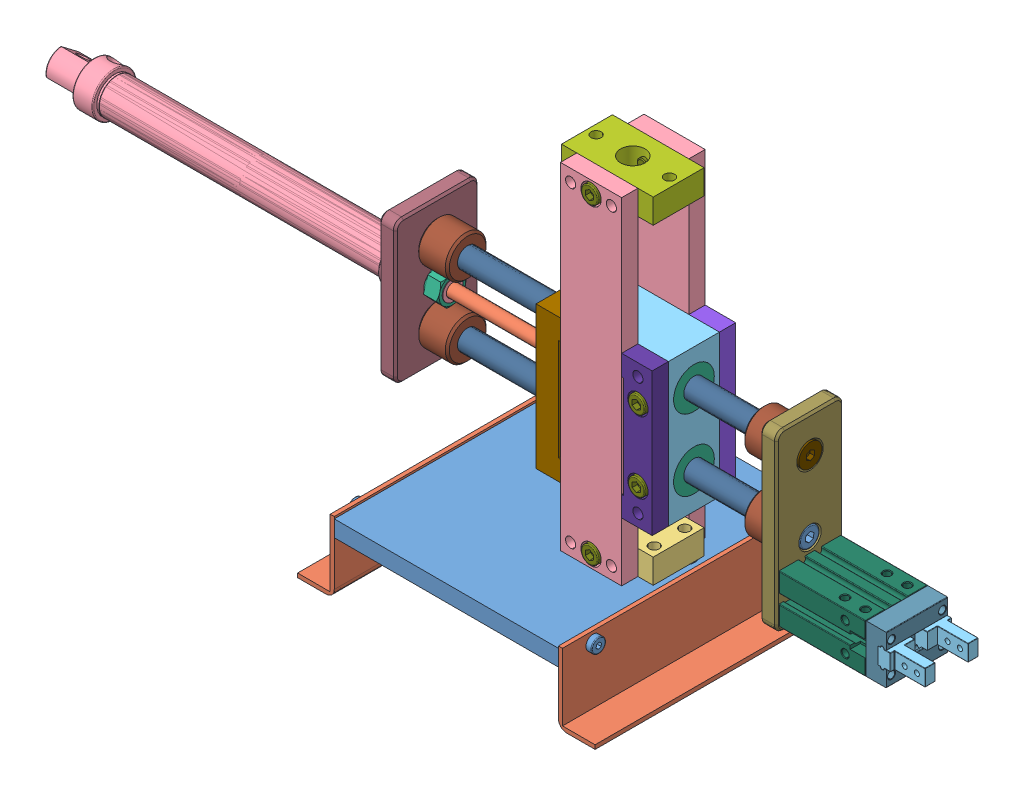
SolidWorks assembly S4, configuration Default. Lengths in mm.
Overall size (436.7 199 125).
52 component instances, 24 part files, 126 mates.
Components (placement in the parent):
- tam de lon-1: tam de lon [Default] at (42.5889 56.6685 101.1963) size (110 8 125)
- khoi do-1: khoi do [Default] at (98.4472 49.4552 163.6963) x (0 0 -1) z (-1 0 0) size (125 35 18)
- khoi do-2: khoi do [Default] at (-13.2695 49.4552 38.6963) x (0 0 1) z (1 0 0) size (125 35 18)
- mieng dem duoi-1: mieng dem duoi [Default] at (71.5889 64.6685 101.1963) size (45 12 25)
- thanh dan huong lon x2-1: thanh dan huong lon x2 [Default] at (71.5889 147.1685 113.6963) x (1 0 0) z (0 -1 0) size (30 8 165)
- thanh dan huong lon x2-2: thanh dan huong lon x2 [Default] at (71.5889 147.1685 88.6963) x (1 0 0) z (0 1 0) size (30 8 165)
- con truot s4 -1: con truot s4  [Default] at (79.0889 93.5395 101.1963) x (-1 0 0) z (0 0 -1) size (45 70 25)
- bac lot-1: bac lot [Default] at (101.5889 111.0395 101.1963) x (0 1 0) z (0 0 1) size (20 12 20)
- bac lot-2: bac lot [Default] at (101.5889 146.0395 101.1963) x (0 1 0) z (0 0 1) size (20 12 20)
- bac lot-3: bac lot [Default] at (56.5889 146.0395 101.1963) x (0 0.381849 -0.924225) z (0 -0.924225 -0.381849) size (20 12 20)
- bac lot-4: bac lot [Default] at (56.5889 111.0395 101.1963) x (0 0.381849 -0.924225) z (0 -0.924225 -0.381849) size (20 12 20)
- mieng dem tren-1: mieng dem tren [Default] at (71.5889 217.6685 101.1963) size (45 12 25)
- thanh dan huong so 2 s4-3: thanh dan huong so 2 s4 [Default] at (94.0889 128.5395 88.6963) x (-1 0 0) z (0 -1 0) size (15 8 70)
- tam dan huong-4: tam dan huong [Default] at (44.5889 128.5395 101.1963) x (0 -1 0) z (0 0 1) size (70 12 41)
- chot dan huong-1: chot dan huong [Default] at (150.5419 146.0395 101.1963) x (0 0.988897 -0.148604) z (0 0.148604 0.988897) size (10 175 10)
- chot dan huong-2: chot dan huong [Default] at (150.5419 111.0395 101.1963) x (0 0.324021 0.94605) z (0 -0.94605 0.324021) size (10 175 10)
- bac chan-1: bac chan [Default] at (150.5419 146.0395 101.1963) x (0 0.942027 0.335537) z (0 -0.335537 0.942027) size (20 15 20)
- bac chan-2: bac chan [Default] at (150.5419 111.0395 101.1963) x (0 1 0) z (0 0 1) size (20 15 20)
- bac chan-3: bac chan [Default] at (-9.4581 146.0395 101.1963) x (0 0.635792 -0.77186) z (0 0.77186 0.635792) size (20 15 20)
- bac chan-4: bac chan [Default] at (-9.4581 111.0395 101.1963) x (0 0.99939 -0.03491) z (0 0.03491 0.99939) size (20 15 20)
- ban canh truoc-1: ban canh truoc [Default] at (150.5419 120.5395 101.1963) x (0 0 -1) z (0 -1 0) size (33 8 86)
- ban canh sau-1: ban canh sau [Default] at (-24.4581 128.5395 101.1963) x (0 0 -1) z (0 1 0) size (41 8 70)
- NMHZ2-16D-2: NMHZ2-16D [Default] at (143.5539 89.9816 123.6032) x (0 0 -1) z (1 0 0) size (30.6 23.6 52.5)
  - NMHZ2-16D Slipway-1: NMHZ2-16D Slipway [Default] at (22.4069 2.6078 57.488) size (30.1 23.6 10)
  - NMHZ2-16D cylinder-2: NMHZ2-16D cylinder [Default] at (22.4069 2.6078 14.988) size (30.6 23.6 42.5)
- socket head cap screw_din-2: socket head cap screw_din [DIN 912 M5 x 16 --- 16N] at (94.5889 146.0395 79.8963) x (0 0 1) z (-1 0 0) size (21 8.5 8.5)
- socket head cap screw_din-5: socket head cap screw_din [DIN 912 M5 x 16 --- 16N] at (94.5889 111.0395 79.8963) x (0 0 1) z (-1 0 0) size (21 8.5 8.5)
- socket head cap screw_din-6: socket head cap screw_din [DIN 912 M5 x 16 --- 16N] at (71.5889 70.6685 79.8963) x (0 0 1) z (-1 0 0) size (21 8.5 8.5)
- socket head cap screw_din-9: socket head cap screw_din [DIN 912 M5 x 8 --- 8N] at (71.5889 70.6685 122.4963) x (0 0 -1) z (1 0 0) size (13 8.5 8.5)
- socket head cap screw_din-10: socket head cap screw_din [DIN 912 M5 x 8 --- 8N] at (45.2889 99.5395 108.6963) size (13 8.5 8.5)
- socket head cap screw_din-11: socket head cap screw_din [DIN 912 M5 x 8 --- 8N] at (45.2889 157.5395 93.6963) size (13 8.5 8.5)
- thanh dan huong s4-1: thanh dan huong s4 [Default] at (94.0889 128.5395 113.6963) x (-1 0 0) z (0 1 0) size (15 8 70)
- socket head cap screw_din-13: socket head cap screw_din [DIN 912 M5 x 12 --- 12N] at (94.5889 111.0395 122.4963) x (0 0 -1) z (1 0 0) size (17 8.5 8.5)
- socket head cap screw_din-14: socket head cap screw_din [DIN 912 M5 x 12 --- 12N] at (94.5889 146.0395 122.4963) x (0 0 -1) z (1 0 0) size (17 8.5 8.5)
- socket head cap screw_din-17: socket head cap screw_din [DIN 912 M5 x 12 --- 12N] at (71.5889 223.6685 79.8963) x (0 0 1) z (-1 0 0) size (17 8.5 8.5)
- socket head cap screw_din-18: socket head cap screw_din [DIN 912 M5 x 12 --- 12N] at (71.5889 223.6685 122.4963) x (0 0 -1) z (1 0 0) size (17 8.5 8.5)
- socket csink head cap screw 10642_din-2: socket csink head cap screw 10642_din [EN ISO 10642 - M6 x 8 - 8N] at (-32.6781 146.0395 101.1963) x (1 0 0) z (0 0.02259 0.999745) size (8 11.34 11.34)
- socket csink head cap screw 10642_din-3: socket csink head cap screw 10642_din [EN ISO 10642 - M6 x 8 - 8N] at (158.7619 146.0395 101.1963) x (-1 0 0) z (0 -0.022602 -0.999745) size (8 11.34 11.34)
- socket head thin cap screw_din-2: socket head thin cap screw_din [DIN 7984 - M6 x 10 --- 7N] at (158.3419 111.0395 101.1963) x (-1 0 0) z (0 0.924225 0.381849) size (14 10 10)
- socket head thin cap screw_din-4: socket head thin cap screw_din [DIN 7984 - M6 x 10 --- 7N] at (-32.2581 111.0395 101.1963) size (14 10 10)
- socket head thin cap screw_din-5: socket head thin cap screw_din [DIN 7984 - M4 x 6 --- 3.9N] at (-17.2111 60.6685 53.6963) size (8.8 7 7)
- socket head thin cap screw_din-6: socket head thin cap screw_din [DIN 7984 - M4 x 6 --- 3.9N] at (-17.2111 60.6685 148.6963) size (8.8 7 7)
- socket head thin cap screw_din-7: socket head thin cap screw_din [DIN 7984 - M4 x 6 --- 3.9N] at (102.3889 60.6685 53.6963) x (-1 0 0) z (0 0.924225 0.381849) size (8.8 7 7)
- socket head thin cap screw_din-8: socket head thin cap screw_din [DIN 7984 - M4 x 6 --- 3.9N] at (102.3889 60.6685 148.6963) x (-1 0 0) z (0 0.924225 0.381849) size (8.8 7 7)
- socket head thin cap screw_din-10: socket head thin cap screw_din [DIN 7984 - M4 x 12 --- 9.9N] at (152.1419 85.2395 112.1963) size (14.8 7 7)
- socket head thin cap screw_din-11: socket head thin cap screw_din [DIN 7984 - M4 x 12 --- 9.9N] at (152.1419 100.2395 90.1963) size (14.8 7 7)
- Rod-1: Rod [Default] at (-92.4392 128.5395 101.1963) x (0 0.871767 -0.48992) z (0 -0.48992 -0.871767) size (6.2 165 6.2)
- Nut 5-1: Nut 5 [Default] at (55.0889 128.5395 101.1963) x (0 0.12782 0.991797) z (0 0.991797 -0.12782) size (11.32 3 9.8)
- 16 X 100 Cylinder bore-2: 16 X 100 Cylinder bore [Default] at (-112.6581 128.5395 101.1963) x (0 0.79605 -0.605231) z (-1 0 0) size (21.5 21.5 192)
- NMHZ2-16D air claw-1: NMHZ2-16D air claw [Default] at (209.0419 92.5895 98.1463) x (0 0 -1) z (1 0 0) size (12 10 21)
- NMHZ2-16D air claw-2: NMHZ2-16D air claw [Default] at (209.0419 92.5895 104.2463) x (0 0 1) z (1 0 0) size (12 10 21)
- hex nut style 2 gradeab_din-2: hex nut style 2 gradeab_din [Hexagon Nut ISO 4033 - M8 - W - N] at (-16.9581 128.5395 101.1963) x (0 0.684808 -0.728723) z (1 0 0) size (13 15.01 7.5)
Mates (geometry in assembly coordinates):
- Parallel1: parallel anti-aligned: plane of tam de lon-1 through (42.5889 64.6685 101.1963) normal (0 1 0); plane of khoi do-1 through (97.5889 30.6685 38.6963) normal (0 -1 0)
- Parallel2: parallel anti-aligned: plane of tam de lon-1 through (97.5889 64.6685 38.6963) normal (1 0 0); plane of khoi do-1 through (97.5889 30.6685 38.6963) normal (-1 0 0)
- Concentric1: concentric aligned: cylinder of tam de lon-1 through (82.5889 60.6685 53.6963) axis (1 0 0) radius 2.5; cylinder of khoi do-1 through (-25.4111 60.6685 53.6963) axis (1 0 0) radius 2.5
- Coincident1: coincident anti-aligned: plane of tam de lon-1 through (97.5889 64.6685 38.6963) normal (1 0 0); plane of khoi do-1 through (97.5889 30.6685 38.6963) normal (-1 0 0)
- Parallel3: parallel anti-aligned: plane of tam de lon-1 through (42.5889 64.6685 101.1963) normal (0 1 0); plane of khoi do-2 through (-12.4111 30.6685 163.6963) normal (0 -1 0)
- Parallel4: parallel anti-aligned: plane of tam de lon-1 through (-12.4111 64.6685 38.6963) normal (-1 0 0); plane of khoi do-2 through (-12.4111 30.6685 163.6963) normal (1 0 0)
- Concentric2: concentric aligned: cylinder of tam de lon-1 through (2.5889 60.6685 148.6963) axis (-1 0 0) radius 2.5; cylinder of khoi do-2 through (110.5889 60.6685 148.6963) axis (-1 0 0) radius 2.5
- Coincident2: coincident anti-aligned: plane of tam de lon-1 through (-12.4111 64.6685 38.6963) normal (-1 0 0); plane of khoi do-2 through (-12.4111 30.6685 163.6963) normal (1 0 0)
- Concentric3: concentric aligned: cylinder of tam de lon-1 through (89.5889 56.6685 93.6963) axis (0 1 0) radius 2.75; cylinder of mieng dem duoi-1 through (89.5889 64.6685 93.6963) axis (0 1 0) radius 2.5
- Concentric4: concentric aligned: cylinder of tam de lon-1 through (53.5889 56.6685 108.6963) axis (0 1 0) radius 2.75; cylinder of mieng dem duoi-1 through (53.5889 64.6685 108.6963) axis (0 1 0) radius 2.5
- Coincident3: coincident anti-aligned: plane of tam de lon-1 through (42.5889 64.6685 101.1963) normal (0 1 0); plane of mieng dem duoi-1 through (71.5889 64.6685 101.1963) normal (0 -1 0)
- Parallel6: parallel anti-aligned: plane of mieng dem duoi-1 through (71.5889 76.6685 101.1963) normal (0 1 0); plane of thanh dan huong lon x2-1 through (56.5889 64.6685 121.6963) normal (0 -1 0)
- Parallel7: parallel anti-aligned: plane of mieng dem duoi-1 through (49.0889 76.6685 113.6963) normal (0 0 1); plane of thanh dan huong lon x2-1 through (71.5889 147.1685 113.6963) normal (0 0 -1)
- Concentric5: concentric anti-aligned: cylinder of mieng dem duoi-1 through (81.5889 70.6685 160.6963) axis (0 0 -1) radius 2.5; cylinder of thanh dan huong lon x2-1 through (81.5889 70.6685 80.4963) axis (0 0 1) radius 2.5
- Coincident4: coincident anti-aligned: plane of mieng dem duoi-1 through (49.0889 76.6685 113.6963) normal (0 0 1); plane of thanh dan huong lon x2-1 through (71.5889 147.1685 113.6963) normal (0 0 -1)
- Parallel8: parallel anti-aligned: plane of mieng dem duoi-1 through (71.5889 76.6685 101.1963) normal (0 1 0); plane of thanh dan huong lon x2-2 through (56.5889 64.6685 80.6963) normal (0 -1 0)
- Parallel9: parallel anti-aligned: plane of mieng dem duoi-1 through (49.0889 76.6685 88.6963) normal (0 0 -1); plane of thanh dan huong lon x2-2 through (71.5889 147.1685 88.6963) normal (0 0 1)
- Concentric6: concentric aligned: cylinder of mieng dem duoi-1 through (81.5889 70.6685 160.6963) axis (0 0 -1) radius 2.5; cylinder of thanh dan huong lon x2-2 through (81.5889 70.6685 121.8963) axis (0 0 -1) radius 2.5
- Coincident5: coincident anti-aligned: plane of mieng dem duoi-1 through (49.0889 76.6685 88.6963) normal (0 0 -1); plane of thanh dan huong lon x2-2 through (71.5889 147.1685 88.6963) normal (0 0 1)
- Parallel10: parallel anti-aligned: plane of mieng dem duoi-1 through (94.0889 76.6685 88.6963) normal (1 0 0); plane of con truot s4 -1 through (56.5889 163.5395 113.6963) normal (-1 0 0)
- Parallel11: parallel aligned: plane of mieng dem duoi-1 through (71.5889 76.6685 101.1963) normal (0 1 0); plane of con truot s4 -1 through (79.0889 163.5395 101.1963) normal (0 1 0)
- Coincident6: coincident anti-aligned: plane of thanh dan huong lon x2-2 through (71.5889 147.1685 88.6963) normal (0 0 1); plane of con truot s4 -1 through (101.5889 163.5395 88.6963) normal (0 0 -1)
- Concentric7: concentric anti-aligned: cylinder of con truot s4 -1 through (126.5889 111.0395 101.1963) axis (-1 0 0) radius 6; cylinder of bac lot-1 through (89.5889 111.0395 101.1963) axis (1 0 0) radius 6
- Coincident14: coincident anti-aligned: plane of con truot s4 -1 through (99.5889 111.0395 101.1963) normal (1 0 0); plane of bac lot-1 through (99.5889 111.0395 101.1963) normal (-1 0 0)
- Concentric8: concentric anti-aligned: cylinder of con truot s4 -1 through (126.5889 146.0395 101.1963) axis (-1 0 0) radius 6; cylinder of bac lot-2 through (89.5889 146.0395 101.1963) axis (1 0 0) radius 6
- Coincident15: coincident anti-aligned: plane of con truot s4 -1 through (99.5889 146.0395 101.1963) normal (1 0 0); plane of bac lot-2 through (99.5889 146.0395 101.1963) normal (-1 0 0)
- Concentric9: concentric aligned: cylinder of con truot s4 -1 through (126.5889 146.0395 101.1963) axis (-1 0 0) radius 6; cylinder of bac lot-3 through (68.5889 146.0395 101.1963) axis (-1 0 0) radius 6
- Coincident16: coincident anti-aligned: plane of con truot s4 -1 through (58.5889 146.0395 101.1963) normal (-1 0 0); plane of bac lot-3 through (58.5889 146.0395 101.1963) normal (1 0 0)
- Concentric10: concentric aligned: cylinder of con truot s4 -1 through (126.5889 111.0395 101.1963) axis (-1 0 0) radius 6; cylinder of bac lot-4 through (68.5889 111.0395 101.1963) axis (-1 0 0) radius 6
- Coincident18: coincident anti-aligned: plane of con truot s4 -1 through (58.5889 111.0395 101.1963) normal (-1 0 0); plane of bac lot-4 through (58.5889 111.0395 101.1963) normal (1 0 0)
- Parallel23: parallel aligned: plane of thanh dan huong lon x2-2 through (56.5889 229.6685 80.6963) normal (0 1 0); plane of mieng dem tren-1 through (71.5889 229.6685 101.1963) normal (0 1 0)
- Concentric12: concentric aligned: cylinder of thanh dan huong lon x2-2 through (61.5889 223.6685 121.8963) axis (0 0 -1) radius 2.5; cylinder of mieng dem tren-1 through (61.5889 223.6685 160.6963) axis (0 0 -1) radius 2.5
- Coincident21: coincident anti-aligned: plane of thanh dan huong lon x2-2 through (71.5889 147.1685 88.6963) normal (0 0 1); plane of mieng dem tren-1 through (49.0889 229.6685 88.6963) normal (0 0 -1)
- Parallel38: parallel aligned: plane of con truot s4 -1 through (79.0889 163.5395 101.1963) normal (0 1 0); plane of thanh dan huong so 2 s4-3 through (101.5889 163.5395 80.6963) normal (0 1 0)
- Parallel39: parallel anti-aligned: plane of con truot s4 -1 through (101.5889 163.5395 88.6963) normal (0 0 -1); plane of thanh dan huong so 2 s4-3 through (94.0889 128.5395 88.6963) normal (0 0 1)
- Coincident32: coincident aligned: plane of con truot s4 -1 through (79.0889 163.5395 101.1963) normal (0 1 0); plane of thanh dan huong so 2 s4-3 through (101.5889 163.5395 80.6963) normal (0 1 0)
- Coincident33: coincident aligned: plane of con truot s4 -1 through (101.5889 163.5395 113.6963) normal (1 0 0); plane of thanh dan huong so 2 s4-3 through (101.5889 163.5395 80.6963) normal (1 0 0)
- Coincident34: coincident anti-aligned: plane of con truot s4 -1 through (101.5889 163.5395 88.6963) normal (0 0 -1); plane of thanh dan huong so 2 s4-3 through (94.0889 128.5395 88.6963) normal (0 0 1)
- Coincident36: coincident anti-aligned: plane of thanh dan huong lon x2-2 through (86.5889 64.6685 80.6963) normal (1 0 0); plane of thanh dan huong so 2 s4-3 through (86.5889 163.5395 80.6963) normal (-1 0 0)
- Parallel46: parallel aligned: plane of con truot s4 -1 through (79.0889 163.5395 101.1963) normal (0 1 0); plane of tam dan huong-4 through (56.5889 163.5395 80.6963) normal (0 1 0)
- Parallel47: parallel anti-aligned: plane of con truot s4 -1 through (56.5889 163.5395 113.6963) normal (-1 0 0); plane of tam dan huong-4 through (55.5889 153.5395 33.6963) normal (1 0 0)
- Coincident40: coincident anti-aligned: plane of con truot s4 -1 through (56.5889 163.5395 113.6963) normal (-1 0 0); plane of tam dan huong-4 through (56.5889 128.5395 101.1963) normal (1 0 0)
- Concentric29: concentric aligned: cylinder of con truot s4 -1 through (71.5889 157.5395 93.6963) axis (-1 0 0) radius 2.5; cylinder of tam dan huong-4 through (132.5889 157.5395 93.6963) axis (-1 0 0) radius 2.75
- Concentric41: concentric anti-aligned: cylinder of bac lot-2 through (116.5889 146.0395 101.1963) axis (-1 0 0) radius 5; cylinder of chot dan huong-1 through (-122.4581 146.0395 101.1963) axis (1 0 0) radius 5
- Concentric42: concentric anti-aligned: cylinder of bac lot-1 through (116.5889 111.0395 101.1963) axis (-1 0 0) radius 5; cylinder of chot dan huong-2 through (-122.4581 111.0395 101.1963) axis (1 0 0) radius 5
- Concentric43: concentric anti-aligned: cylinder of chot dan huong-1 through (-122.4581 146.0395 101.1963) axis (1 0 0) radius 5; cylinder of bac chan-1 through (150.5419 146.0395 101.1963) axis (-1 0 0) radius 5
- Coincident53: coincident aligned: plane of chot dan huong-1 through (150.5419 146.0395 101.1963) normal (1 0 0); plane of bac chan-1 through (150.5419 146.0395 101.1963) normal (1 0 0)
- Concentric44: concentric anti-aligned: cylinder of chot dan huong-2 through (-122.4581 111.0395 101.1963) axis (1 0 0) radius 5; cylinder of bac chan-2 through (150.5419 111.0395 101.1963) axis (-1 0 0) radius 5
- Coincident54: coincident aligned: plane of chot dan huong-2 through (150.5419 111.0395 101.1963) normal (1 0 0); plane of bac chan-2 through (150.5419 111.0395 101.1963) normal (1 0 0)
- Concentric45: concentric anti-aligned: cylinder of chot dan huong-1 through (-122.4581 146.0395 101.1963) axis (1 0 0) radius 5; cylinder of bac chan-3 through (-9.4581 146.0395 101.1963) axis (-1 0 0) radius 5
- Coincident55: coincident aligned: plane of chot dan huong-1 through (-24.4581 146.0395 101.1963) normal (-1 0 0); plane of bac chan-3 through (-24.4581 146.0395 101.1963) normal (-1 0 0)
- Coincident57: coincident aligned: plane of chot dan huong-2 through (-24.4581 111.0395 101.1963) normal (-1 0 0); plane of bac chan-4 through (-24.4581 111.0395 101.1963) normal (-1 0 0)
- Concentric47: concentric aligned: cylinder of chot dan huong-1 through (130.5419 146.0395 101.1963) axis (1 0 0) radius 3; cylinder of ban canh truoc-1 through (150.5419 146.0395 101.1963) axis (1 0 0) radius 3.3
- Concentric48: concentric aligned: cylinder of chot dan huong-2 through (130.5419 111.0395 101.1963) axis (1 0 0) radius 3; cylinder of ban canh truoc-1 through (150.5419 111.0395 101.1963) axis (1 0 0) radius 3.3
- Coincident58: coincident anti-aligned: plane of chot dan huong-1 through (150.5419 146.0395 101.1963) normal (1 0 0); plane of ban canh truoc-1 through (150.5419 120.5395 101.1963) normal (-1 0 0)
- Coincident59: coincident anti-aligned: plane of chot dan huong-2 through (150.5419 111.0395 101.1963) normal (1 0 0); plane of ban canh truoc-1 through (150.5419 120.5395 101.1963) normal (-1 0 0)
- Concentric49: concentric aligned: cylinder of chot dan huong-1 through (-4.4581 146.0395 101.1963) axis (-1 0 0) radius 3; cylinder of ban canh sau-1 through (-24.4581 146.0395 101.1963) axis (-1 0 0) radius 3.3
- Concentric50: concentric aligned: cylinder of chot dan huong-2 through (-4.4581 111.0395 101.1963) axis (-1 0 0) radius 3; cylinder of ban canh sau-1 through (-24.4581 111.0395 101.1963) axis (-1 0 0) radius 3.3
- Coincident60: coincident anti-aligned: plane of chot dan huong-1 through (-24.4581 146.0395 101.1963) normal (-1 0 0); plane of ban canh sau-1 through (-24.4581 128.5395 101.1963) normal (1 0 0)
- Coincident61: coincident anti-aligned: plane of chot dan huong-2 through (-24.4581 111.0395 101.1963) normal (-1 0 0); plane of ban canh sau-1 through (-24.4581 128.5395 101.1963) normal (1 0 0)
- Concentric55: concentric anti-aligned: cylinder of ban canh truoc-1 through (150.5419 85.2395 112.1963) axis (1 0 0) radius 2.25; cylinder of NMHZ2-16D-2/NMHZ2-16D cylinder-2 through (173.5419 85.2395 112.1963) axis (-1 0 0) radius 2
- Concentric56: concentric anti-aligned: cylinder of ban canh truoc-1 through (150.5419 100.2395 90.1963) axis (1 0 0) radius 2.25; cylinder of NMHZ2-16D-2/NMHZ2-16D cylinder-2 through (173.5419 100.2395 90.1963) axis (-1 0 0) radius 2
- Coincident62: coincident anti-aligned: plane of ban canh truoc-1 through (158.5419 120.5395 101.1963) normal (1 0 0); plane of NMHZ2-16D-2/NMHZ2-16D cylinder-2 through (158.5419 92.5895 101.1963) normal (-1 0 0)
- Concentric57: concentric anti-aligned: cylinder of chot dan huong-2 through (-122.4581 111.0395 101.1963) axis (1 0 0) radius 5; cylinder of bac chan-4 through (-9.4581 111.0395 101.1963) axis (-1 0 0) radius 5
- Concentric61: concentric aligned: cylinder of thanh dan huong so 2 s4-3 through (94.5889 146.0395 88.6963) axis (0 0 -1) radius 2.75; cylinder of socket head cap screw_din-2 through (94.5889 146.0395 48.1463) axis (0 0 -1) radius 4.25
- Coincident66: coincident anti-aligned: plane of thanh dan huong so 2 s4-3 through (94.5889 146.0395 84.8963) normal (0 0 -1); plane of socket head cap screw_din-2 through (94.5889 150.2895 84.8963) normal (0 0 1)
- Concentric64: concentric aligned: cylinder of thanh dan huong so 2 s4-3 through (94.5889 111.0395 88.6963) axis (0 0 -1) radius 2.75; cylinder of socket head cap screw_din-5 through (94.5889 111.0395 48.1463) axis (0 0 -1) radius 4.25
- Coincident69: coincident anti-aligned: plane of thanh dan huong so 2 s4-3 through (94.5889 111.0395 84.8963) normal (0 0 -1); plane of socket head cap screw_din-5 through (94.5889 115.2895 84.8963) normal (0 0 1)
- Concentric651: concentric aligned: cylinder of thanh dan huong lon x2-2 through (71.5889 70.6685 88.6963) axis (0 0 -1) radius 2.75; cylinder of socket head cap screw_din-6 through (71.5889 70.6685 48.1463) axis (0 0 -1) radius 4.25
- Coincident701: coincident anti-aligned: plane of thanh dan huong lon x2-2 through (71.5889 70.6685 84.8963) normal (0 0 -1); plane of socket head cap screw_din-6 through (71.5889 74.9185 84.8963) normal (0 0 1)
- Concentric66: concentric aligned: cylinder of thanh dan huong lon x2-1 through (71.5889 70.6685 113.6963) axis (0 0 1) radius 2.75; cylinder of socket head cap screw_din-9 through (71.5889 70.6685 154.2463) axis (0 0 1) radius 4.25
- Coincident71: coincident anti-aligned: plane of thanh dan huong lon x2-1 through (71.5889 70.6685 117.4963) normal (0 0 1); plane of socket head cap screw_din-9 through (71.5889 74.9185 117.4963) normal (0 0 -1)
- Concentric67: concentric aligned: cylinder of tam dan huong-4 through (132.5889 99.5395 108.6963) axis (-1 0 0) radius 2.75; cylinder of socket head cap screw_din-10 through (13.5389 99.5395 108.6963) axis (-1 0 0) radius 4.25
- Coincident72: coincident anti-aligned: plane of tam dan huong-4 through (50.2889 99.5395 108.6963) normal (-1 0 0); plane of socket head cap screw_din-10 through (50.2889 103.7895 108.6963) normal (1 0 0)
- Concentric68: concentric aligned: cylinder of tam dan huong-4 through (132.5889 157.5395 93.6963) axis (-1 0 0) radius 2.75; cylinder of socket head cap screw_din-11 through (13.5389 157.5395 93.6963) axis (-1 0 0) radius 4.25
- Coincident73: coincident anti-aligned: plane of tam dan huong-4 through (50.2889 157.5395 93.6963) normal (-1 0 0); plane of socket head cap screw_din-11 through (50.2889 161.7895 93.6963) normal (1 0 0)
- Parallel62: parallel aligned: plane of con truot s4 -1 through (101.5889 163.5395 113.6963) normal (0 0 1); plane of thanh dan huong s4-1 through (94.0889 128.5395 121.6963) normal (0 0 1)
- Parallel63: parallel aligned: plane of con truot s4 -1 through (101.5889 163.5395 113.6963) normal (1 0 0); plane of thanh dan huong s4-1 through (101.5889 93.5395 121.6963) normal (1 0 0)
- Concentric71: concentric anti-aligned: cylinder of con truot s4 -1 through (94.5889 111.0395 124.6963) axis (0 0 -1) radius 2.5; cylinder of thanh dan huong s4-1 through (94.5889 111.0395 113.6963) axis (0 0 1) radius 2.75
- Coincident76: coincident anti-aligned: plane of con truot s4 -1 through (101.5889 163.5395 113.6963) normal (0 0 1); plane of thanh dan huong s4-1 through (94.0889 128.5395 113.6963) normal (0 0 -1)
- Concentric72: concentric aligned: cylinder of thanh dan huong s4-1 through (94.5889 111.0395 113.6963) axis (0 0 1) radius 2.75; cylinder of socket head cap screw_din-13 through (94.5889 111.0395 154.2463) axis (0 0 1) radius 4.25
- Coincident77: coincident anti-aligned: plane of thanh dan huong s4-1 through (94.5889 111.0395 117.4963) normal (0 0 1); plane of socket head cap screw_din-13 through (94.5889 115.2895 117.4963) normal (0 0 -1)
- Concentric73: concentric aligned: cylinder of thanh dan huong s4-1 through (94.5889 146.0395 113.6963) axis (0 0 1) radius 2.75; cylinder of socket head cap screw_din-14 through (94.5889 146.0395 154.2463) axis (0 0 1) radius 4.25
- Coincident78: coincident anti-aligned: plane of thanh dan huong s4-1 through (94.5889 146.0395 117.4963) normal (0 0 1); plane of socket head cap screw_din-14 through (94.5889 150.2895 117.4963) normal (0 0 -1)
- Concentric76: concentric aligned: cylinder of thanh dan huong lon x2-2 through (71.5889 223.6685 84.8963) axis (0 0 -1) radius 5; cylinder of socket head cap screw_din-17 through (71.5889 223.6685 48.1463) axis (0 0 -1) radius 4.25
- Coincident81: coincident anti-aligned: plane of thanh dan huong lon x2-2 through (71.5889 223.6685 84.8963) normal (0 0 -1); plane of socket head cap screw_din-17 through (71.5889 227.9185 84.8963) normal (0 0 1)
- Concentric77: concentric aligned: cylinder of thanh dan huong lon x2-1 through (71.5889 223.6685 113.6963) axis (0 0 1) radius 2.75; cylinder of socket head cap screw_din-18 through (71.5889 223.6685 154.2463) axis (0 0 1) radius 4.25
- Coincident82: coincident anti-aligned: plane of thanh dan huong lon x2-1 through (71.5889 223.6685 117.4963) normal (0 0 1); plane of socket head cap screw_din-18 through (71.5889 227.9185 117.4963) normal (0 0 -1)
- Coincident83: coincident aligned: cone of ban canh sau-1 through (-29.2581 146.0395 101.1963) axis (1 0 0); cone of socket csink head cap screw 10642_din-2 through (-31.6281 146.0395 101.1963) axis (1 0 0)
- Coincident84: coincident aligned: cone of ban canh truoc-1 through (155.3419 146.0395 101.1963) axis (-1 0 0); cone of socket csink head cap screw 10642_din-3 through (157.7119 146.0395 101.1963) axis (-1 0 0)
- Concentric78: concentric aligned: cylinder of ban canh truoc-1 through (150.5419 111.0395 101.1963) axis (1 0 0) radius 3.3; cylinder of socket head thin cap screw_din-2 through (190.0919 111.0395 101.1963) axis (1 0 0) radius 5
- Coincident85: coincident anti-aligned: plane of ban canh truoc-1 through (154.3419 111.0395 101.1963) normal (1 0 0); plane of socket head thin cap screw_din-2 through (154.3419 109.1302 105.8174) normal (-1 0 0)
- Concentric79: concentric aligned: cylinder of ban canh sau-1 through (-24.4581 111.0395 101.1963) axis (-1 0 0) radius 3.3; cylinder of socket head thin cap screw_din-4 through (-64.0081 111.0395 101.1963) axis (-1 0 0) radius 5
- Coincident86: coincident anti-aligned: plane of ban canh sau-1 through (-28.2581 111.0395 101.1963) normal (-1 0 0); plane of socket head thin cap screw_din-4 through (-28.2581 116.0395 101.1963) normal (1 0 0)
- Concentric80: concentric aligned: cylinder of khoi do-2 through (110.5889 60.6685 53.6963) axis (-1 0 0) radius 2.5; cylinder of socket head thin cap screw_din-5 through (-48.9611 60.6685 53.6963) axis (-1 0 0) radius 3.5
- Coincident87: coincident anti-aligned: plane of khoi do-2 through (-14.4111 32.6685 163.6963) normal (-1 0 0); plane of socket head thin cap screw_din-5 through (-14.4111 64.1685 53.6963) normal (1 0 0)
- Concentric81: concentric aligned: cylinder of khoi do-2 through (110.5889 60.6685 148.6963) axis (-1 0 0) radius 2.5; cylinder of socket head thin cap screw_din-6 through (-48.9611 60.6685 148.6963) axis (-1 0 0) radius 3.5
- Coincident88: coincident anti-aligned: plane of khoi do-2 through (-14.4111 32.6685 163.6963) normal (-1 0 0); plane of socket head thin cap screw_din-6 through (-14.4111 64.1685 148.6963) normal (1 0 0)
- Concentric82: concentric aligned: cylinder of khoi do-1 through (-25.4111 60.6685 53.6963) axis (1 0 0) radius 2.5; cylinder of socket head thin cap screw_din-7 through (134.1389 60.6685 53.6963) axis (1 0 0) radius 3.5
- Coincident89: coincident anti-aligned: plane of khoi do-1 through (99.5889 32.6685 38.6963) normal (1 0 0); plane of socket head thin cap screw_din-7 through (99.5889 59.332 56.9311) normal (-1 0 0)
- Concentric83: concentric aligned: cylinder of khoi do-1 through (-25.4111 60.6685 148.6963) axis (1 0 0) radius 2.5; cylinder of socket head thin cap screw_din-8 through (134.1389 60.6685 148.6963) axis (1 0 0) radius 3.5
- Coincident90: coincident anti-aligned: plane of khoi do-1 through (99.5889 32.6685 38.6963) normal (1 0 0); plane of socket head thin cap screw_din-8 through (99.5889 59.332 151.9311) normal (-1 0 0)
- Concentric84: concentric anti-aligned: cylinder of ban canh truoc-1 through (150.5419 85.2395 112.1963) axis (1 0 0) radius 2.25; cylinder of socket head thin cap screw_din-10 through (120.3919 85.2395 112.1963) axis (-1 0 0) radius 3.5
- Coincident91: coincident anti-aligned: plane of ban canh truoc-1 through (154.9419 85.2395 112.1963) normal (-1 0 0); plane of socket head thin cap screw_din-10 through (154.9419 88.7395 112.1963) normal (1 0 0)
- Concentric85: concentric aligned: cylinder of ban canh truoc-1 through (154.9419 100.2395 90.1963) axis (-1 0 0) radius 4; cylinder of socket head thin cap screw_din-11 through (120.3919 100.2395 90.1963) axis (-1 0 0) radius 3.5
- Coincident92: coincident anti-aligned: plane of ban canh truoc-1 through (154.9419 100.2395 90.1963) normal (-1 0 0); plane of socket head thin cap screw_din-11 through (154.9419 103.7395 90.1963) normal (1 0 0)
- LimitDistance3: limit distance = 33.9531 mm anti-aligned: plane of bac chan-1 through (135.5419 146.0395 101.1963) normal (-1 0 0); plane of con truot s4 -1 through (101.5889 163.5395 113.6963) normal (1 0 0)
- LimitDistance4: limit distance = 54.129 mm anti-aligned: plane of tam dan huong-4 through (56.5889 163.5395 80.6963) normal (0 1 0); plane of mieng dem tren-1 through (71.5889 217.6685 101.1963) normal (0 -1 0)
- Concentric93: concentric anti-aligned: cylinder of con truot s4 -1 through (71.5889 128.5395 101.1963) axis (-1 0 0) radius 2.5; cylinder of Rod-1 through (52.5608 128.5395 101.1963) axis (1 0 0) radius 2.6
- Concentric94: concentric anti-aligned: cylinder of Rod-1 through (52.5608 128.5395 101.1963) axis (1 0 0) radius 2.6; cylinder of Nut 5-1 through (56.5889 128.5395 101.1963) axis (-1 0 0) radius 2.75
- Lock4: lock: unknown of Rod-1; unknown of Nut 5-1
- Coincident99: coincident anti-aligned: plane of con truot s4 -1 through (56.5889 163.5395 113.6963) normal (-1 0 0); plane of Nut 5-1 through (56.5889 128.5395 101.1963) normal (1 0 0)
- Concentric95: concentric anti-aligned: cylinder of Rod-1 through (72.5608 128.5395 101.1963) axis (-1 0 0) radius 3.1; cylinder of 16 X 100 Cylinder bore-2 through (-191.6581 128.5395 101.1963) axis (1 0 0) radius 3.25
- LimitDistance9: limit distance = 90.2189 mm anti-aligned: plane of Rod-1 through (-92.4392 128.5395 101.1963) normal (-1 0 0); plane of 16 X 100 Cylinder bore-2 through (-182.6581 128.5395 101.1963) normal (1 0 0)
- Parallel64: parallel anti-aligned: plane of NMHZ2-16D-2/NMHZ2-16D Slipway-1 through (207.0419 92.5895 123.6963) normal (1 0 0); plane of NMHZ2-16D air claw-1 through (207.0419 92.5895 86.1463) normal (-1 0 0)
- Coincident105: coincident anti-aligned: plane of NMHZ2-16D-2/NMHZ2-16D Slipway-1 through (207.0419 92.5895 123.6963) normal (1 0 0); plane of NMHZ2-16D air claw-1 through (207.0419 92.5895 86.1463) normal (-1 0 0)
- Concentric97: concentric anti-aligned: cylinder of NMHZ2-16D-2/NMHZ2-16D Slipway-1 through (209.0419 96.5895 123.6963) axis (0 0 -1) radius 1; cylinder of NMHZ2-16D air claw-1 through (209.0419 96.5895 86.1463) axis (0 0 1) radius 1
- Parallel65: parallel anti-aligned: plane of NMHZ2-16D-2/NMHZ2-16D Slipway-1 through (207.0419 92.5895 123.6963) normal (1 0 0); plane of NMHZ2-16D air claw-2 through (207.0419 92.5895 116.2463) normal (-1 0 0)
- Parallel66: parallel anti-aligned: plane of NMHZ2-16D air claw-1 through (209.0419 96.5895 86.1463) normal (0 1 0); plane of NMHZ2-16D air claw-2 through (209.0419 88.5895 116.2463) normal (0 -1 0)
- Coincident106: coincident anti-aligned: plane of NMHZ2-16D-2/NMHZ2-16D Slipway-1 through (207.0419 92.5895 123.6963) normal (1 0 0); plane of NMHZ2-16D air claw-2 through (207.0419 92.5895 116.2463) normal (-1 0 0)
- Concentric98: concentric aligned: cylinder of NMHZ2-16D-2/NMHZ2-16D Slipway-1 through (209.0419 96.5895 123.6963) axis (0 0 -1) radius 1; cylinder of NMHZ2-16D air claw-2 through (209.0419 96.5895 116.2463) axis (0 0 -1) radius 1
- Coincident107: coincident aligned: plane of NMHZ2-16D-2/NMHZ2-16D Slipway-1 through (211.0419 110.0807 86.1463) normal (0 0 -1); plane of NMHZ2-16D air claw-1 through (209.0419 92.5895 86.1463) normal (0 0 -1)
- Coincident108: coincident aligned: plane of NMHZ2-16D-2/NMHZ2-16D Slipway-1 through (211.0419 110.0807 116.2463) normal (0 0 1); plane of NMHZ2-16D air claw-2 through (209.0419 92.5895 116.2463) normal (0 0 1)
- Coincident702: coincident anti-aligned: plane of ban canh sau-1 through (-28.4581 128.5395 101.1963) normal (-1 0 0); plane of 16 X 100 Cylinder bore-2 through (-28.4581 128.5395 101.1963) normal (1 0 0)
- Concentric652: concentric aligned: cylinder of 16 X 100 Cylinder bore-2 through (-75.2829 128.5395 101.1963) axis (1 0 0) radius 5; cylinder of hex nut style 2 gradeab_din-2 through (-41.9956 128.5395 101.1963) axis (1 0 0) radius 4
- Coincident703: coincident anti-aligned: plane of ban canh sau-1 through (-24.4581 128.5395 101.1963) normal (1 0 0); plane of hex nut style 2 gradeab_din-2 through (-24.4581 119.637 110.6697) normal (-1 0 0)
